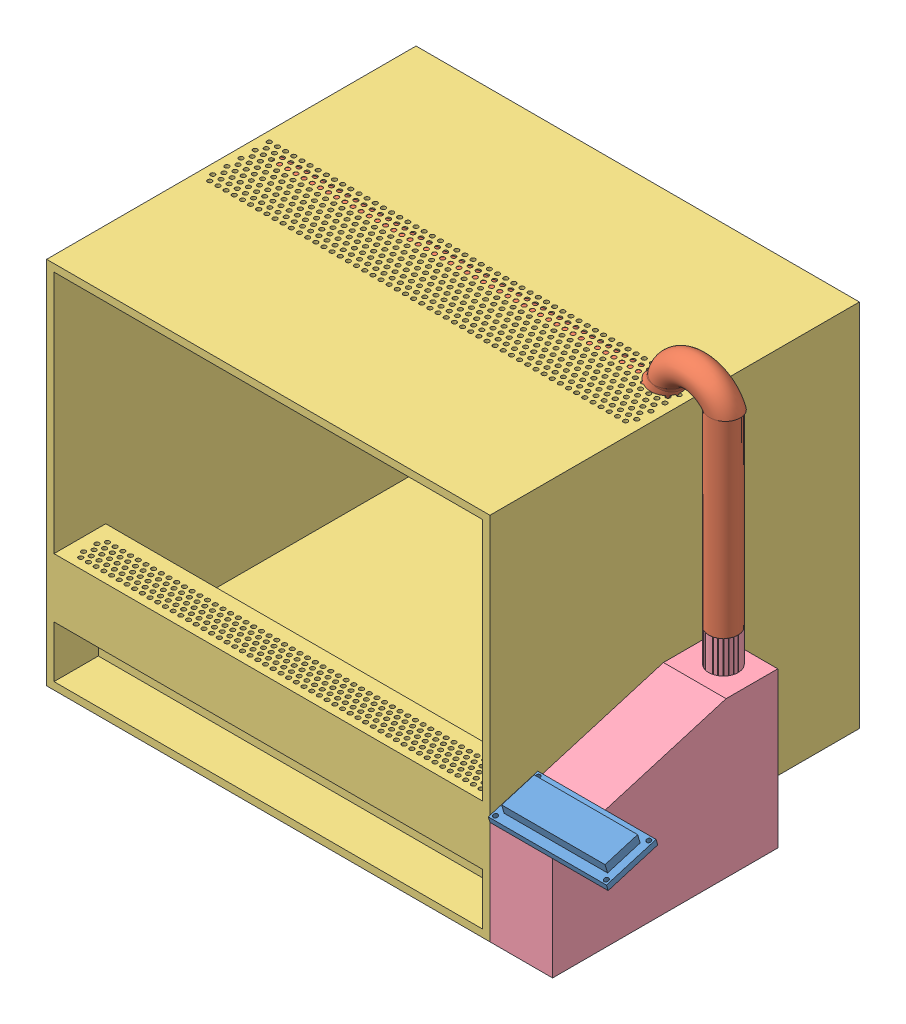
SolidWorks assembly Złożenie1, configuration Domyślna. Lengths in mm.
Overall size (380 294.12 252.86).
4 component instances, 4 part files, 8 mates.
Components (placement in the parent):
- LCD-1: LCD [Domyślna] at (122.8295 -30.5355 76.9294) x (1 0 0) z (0 -0.2857 0.958319) size (80 10 35)
- naprysk-1: naprysk [Domyślna] at (-88.9723 134.4647 -43.0915) size (315.19 189.12 23.97)
- Terrarium_glass_frame-1: Terrarium_glass_frame [Domyślna] at (-67.1705 19.4647 -31.3) size (300 250 250)
- zbiornik na wodę-1: zbiornik na wodę [Domyślna] at (104.0295 -105.5353 17.5) size (42.4 127 152.4)
Mates (geometry in assembly coordinates):
- Wspólnie1: coincident anti-aligned: plane of Terrarium_glass_frame-1 through (82.8295 -105.5353 -156.3) normal (1 0 0); plane of zbiornik na wodę-1 through (82.8295 -35.5353 93.7) normal (-1 0 0)
- Wspólnie3: coincident aligned: plane of Terrarium_glass_frame-1; plane of zbiornik na wodę-1
- Wspólnie4: coincident anti-aligned: plane of naprysk-1; plane of zbiornik na wodę-1
- Wspólnie5: coincident aligned: plane of Terrarium_glass_frame-1; plane of zbiornik na wodę-1
- Koncentryczne1: concentric anti-aligned: cylinder of naprysk-1 through (104.0295 -0.5353 -43.0915) axis (0 1 0) radius 10; cylinder of zbiornik na wodę-1 through (104.0295 21.4647 -43.0915) axis (0 -1 0) radius 10
- Wspólnie7: coincident anti-aligned: plane of LCD-1 through (122.8295 -30.5355 76.9294) normal (0 -0.958319 -0.2857); plane of zbiornik na wodę-1 through (281.5969 -0.5353 -23.7) normal (0 0.958319 0.2857)
- Wspólnie8: coincident anti-aligned: plane of LCD-1 through (82.8295 -31.702 94.8428) normal (-1 0 0); plane of Terrarium_glass_frame-1 through (82.8295 -105.5353 -156.3) normal (1 0 0)
- Wspólnie9: coincident: plane of LCD-1 through (162.8295 -31.702 94.8428) normal (0 -0.2857 0.958319); line of zbiornik na wodę-1 through (82.8295 -35.5353 93.7) axis (1 0 0)
